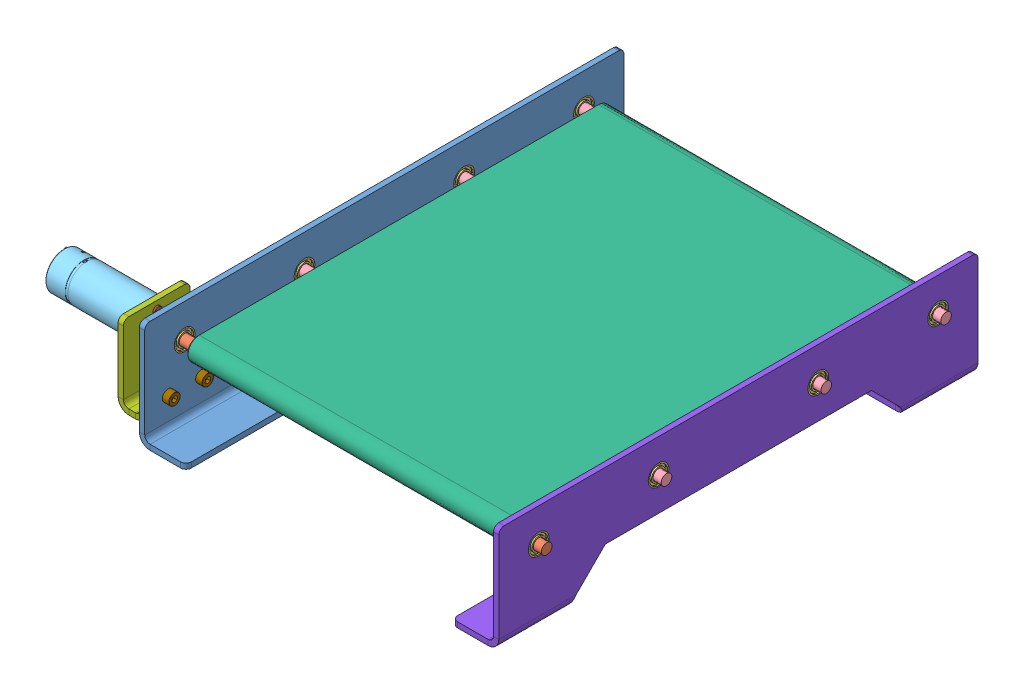
SolidWorks assembly Conveyor, configuration Default. Lengths in mm.
Overall size (367.55 80 360).
25 component instances, 11 part files, 54 mates.
Components (placement in the parent):
- ConveyorFrame2-1: ConveyorFrame2 [Default] at (-55.1725 55.3109 -170.5228) size (35 80 360)
- RollerMotorShaft-1: RollerMotorShaft [Default] at (200.8275 30.3109 159.4772) x (0 -0.190397 0.981707) z (-1 0 0) size (15 15 292)
- SKF - 618-8 - 12,SI,NC,12_68-4: SKF - 618-8 - 12,SI,NC,12_68 [SKF - 618-8 - 12,SI,NC,12_68] at (-53.1725 30.3109 -140.5228) x (-1 0 0) z (0 -0.925656 -0.378366) size (4 16 16)
- SKF - 618-8 - 12,SI,NC,12_68-5: SKF - 618-8 - 12,SI,NC,12_68 [SKF - 618-8 - 12,SI,NC,12_68] at (-53.1725 30.3109 -50.5228) size (4 16 16)
- SKF - 618-8 - 12,SI,NC,12_68-6: SKF - 618-8 - 12,SI,NC,12_68 [SKF - 618-8 - 12,SI,NC,12_68] at (-53.1725 30.3109 69.4772) x (1 0 0) z (0 0.002709 0.999996) size (4 16 16)
- SKF - 618-8 - 12,SI,NC,12_68-7: SKF - 618-8 - 12,SI,NC,12_68 [SKF - 618-8 - 12,SI,NC,12_68] at (-53.1725 30.3109 159.4772) size (4 16 16)
- SKF - 618-8 - 12,SI,NC,12_68-8: SKF - 618-8 - 12,SI,NC,12_68 [SKF - 618-8 - 12,SI,NC,12_68] at (212.8275 30.3109 -140.5228) x (1 0 0) z (0 -0.084259 0.996444) size (4 16 16)
- SKF - 618-8 - 12,SI,NC,12_68-9: SKF - 618-8 - 12,SI,NC,12_68 [SKF - 618-8 - 12,SI,NC,12_68] at (212.8275 30.3109 -50.5228) size (4 16 16)
- SKF - 618-8 - 12,SI,NC,12_68-10: SKF - 618-8 - 12,SI,NC,12_68 [SKF - 618-8 - 12,SI,NC,12_68] at (212.8275 30.3109 69.4772) x (1 0 0) z (0 0.283229 0.959052) size (4 16 16)
- SKF - 618-8 - 12,SI,NC,12_68-11: SKF - 618-8 - 12,SI,NC,12_68 [SKF - 618-8 - 12,SI,NC,12_68] at (212.8275 30.3109 159.4772) x (1 0 0) z (0 0.083715 0.99649) size (4 16 16)
- Roller-2: Roller [Default] at (-41.1725 30.3109 69.4772) x (0 0 -1) z (1 0 0) size (15 15 282)
- Roller-3: Roller [Default] at (-41.1725 30.3109 -140.5228) x (0 0 -1) z (1 0 0) size (15 15 282)
- Roller-4: Roller [Default] at (200.8275 30.3109 -50.5228) x (0 0.924225 0.381849) z (-1 0 0) size (15 15 282)
- DC_MOTOR_(Brushless DC Inrunner Motor)-1: DC_MOTOR_(Brushless DC Inrunner Motor) [Default] at (-76.1725 30.3109 159.4772) x (1 0 0) z (0 0.866025 0.5) size (82.15 28 28)
- ConveyorBelt-1: ConveyorBelt [Default] at (-40.1725 12.0227 98.7904) x (0 0 -1) z (1 0 0) size (317 17 240)
- MotorBracketConveyor-1: MotorBracketConveyor [Default] at (-76.1725 45.3109 184.4772) x (0 0 -1) z (1 0 0) size (50 60 21)
- ConveyorFrame-4: ConveyorFrame [Default] at (214.8275 55.3109 189.4772) x (-1 0 0) z (0 0 -1) size (35 80 360)
- IS 2269 - M5 x 16-N-1: IS 2269 - M5 x 16-N [IS 2269 - M5 x 16-N] at (-46.1725 0.3109 146.9772) x (-1 0 0) z (0 0.924225 0.381849) size (21 8.5 8.5)
- IS 2269 - M5 x 16-N-2: IS 2269 - M5 x 16-N [IS 2269 - M5 x 16-N] at (-46.1725 0.3109 171.9772) x (-1 0 0) z (0 0.924225 0.381849) size (21 8.5 8.5)
- IS 1363-2 - M5-N-1: IS 1363-2 - M5-N [IS 1363-2 - M5-N] at (-64.7725 0.3109 146.9772) x (0 0 1) z (-1 0 0) size (8 9.24 5.6)
- IS 1363-2 - M5-N-2: IS 1363-2 - M5-N [IS 1363-2 - M5-N] at (-64.7725 0.3109 171.9772) x (0 0 1) z (-1 0 0) size (8 9.24 5.6)
- IS 7483 - M3 x 6 - Z -- 6N-1: IS 7483 - M3 x 6 - Z -- 6N [IS 7483 - M3 x 6 - Z -- 6N] at (-69.7725 30.3109 168.4772) x (-1 0 0) z (0 -0.924225 -0.381849) size (8.35 5.6 5.6)
- IS 7483 - M3 x 6 - Z -- 6N-2: IS 7483 - M3 x 6 - Z -- 6N [IS 7483 - M3 x 6 - Z -- 6N] at (-69.7725 21.3109 159.4772) x (-1 0 0) z (0 0 1) size (8.35 5.6 5.6)
- IS 7483 - M3 x 6 - Z -- 6N-3: IS 7483 - M3 x 6 - Z -- 6N [IS 7483 - M3 x 6 - Z -- 6N] at (-69.7725 39.3109 159.4772) x (-1 0 0) z (0 -0.924225 -0.381849) size (8.35 5.6 5.6)
- IS 7483 - M3 x 6 - Z -- 6N-4: IS 7483 - M3 x 6 - Z -- 6N [IS 7483 - M3 x 6 - Z -- 6N] at (-69.7725 30.3109 150.4772) x (-1 0 0) z (0 -0.924225 -0.381849) size (8.35 5.6 5.6)
Mates (geometry in assembly coordinates):
- Concentric15: concentric anti-aligned: cylinder of RollerMotorShaft-1 through (220.8275 30.3109 159.4772) axis (-1 0 0) radius 4; cylinder of SKF - 618-8 - 12,SI,NC,12_68-11 through (192.19 30.3109 159.4772) axis (1 0 0) radius 4
- Concentric16: concentric anti-aligned: cylinder of SKF - 618-8 - 12,SI,NC,12_68-10 through (192.19 30.3109 69.4772) axis (1 0 0) radius 4; cylinder of Roller-2 through (220.8275 30.3109 69.4772) axis (-1 0 0) radius 4
- Concentric17: concentric aligned: cylinder of SKF - 618-8 - 12,SI,NC,12_68-5 through (-73.81 30.3109 -50.5228) axis (1 0 0) radius 4; cylinder of Roller-4 through (-61.1725 30.3109 -50.5228) axis (1 0 0) radius 4
- Concentric18: concentric anti-aligned: cylinder of SKF - 618-8 - 12,SI,NC,12_68-8 through (192.19 30.3109 -140.5228) axis (1 0 0) radius 4; cylinder of Roller-3 through (220.8275 30.3109 -140.5228) axis (-1 0 0) radius 4
- Concentric22: concentric aligned: cylinder of Roller-3 through (200.8275 30.3109 -140.5228) axis (-1 0 0) radius 7.5; cylinder of ConveyorBelt-1 through (199.8275 30.3109 -140.5228) axis (-1 0 0) radius 7.5
- Concentric23: concentric anti-aligned: cylinder of RollerMotorShaft-1 through (-71.1725 30.3109 159.4772) axis (1 0 0) radius 4; cylinder of DC_MOTOR_(Brushless DC Inrunner Motor)-1 through (-64.5725 30.3109 159.4772) axis (-1 0 0) radius 1.5875
- Distance8: distance = 2 mm anti-aligned: plane of RollerMotorShaft-1 through (-71.1725 30.3109 159.4772) normal (-1 0 0); plane of DC_MOTOR_(Brushless DC Inrunner Motor)-1 through (-73.1725 30.3109 159.4772) normal (1 0 0)
- Concentric26: concentric aligned: cylinder of RollerMotorShaft-1 through (-71.1725 30.3109 159.4772) axis (1 0 0) radius 4; cylinder of MotorBracketConveyor-1 through (-72.1725 30.3109 159.4772) axis (1 0 0) radius 5.5
- Coincident20: coincident anti-aligned: plane of DC_MOTOR_(Brushless DC Inrunner Motor)-1 through (-76.1725 30.3109 159.4772) normal (1 0 0); plane of MotorBracketConveyor-1 through (-76.1725 -10.6891 134.4772) normal (-1 0 0)
- Concentric27: concentric aligned: cylinder of DC_MOTOR_(Brushless DC Inrunner Motor)-1 through (-83.1725 39.3109 159.4772) axis (1 0 0) radius 1.5; cylinder of MotorBracketConveyor-1 through (-72.1725 39.3109 159.4772) axis (1 0 0) radius 1.5
- Distance10: distance = 270 mm anti-aligned: plane of ConveyorFrame2-1 through (-55.1725 -20.6891 189.4772) normal (-1 0 0); plane of ConveyorFrame-4 through (214.8275 -20.6891 -170.5228) normal (1 0 0)
- Distance11: distance = 10 mm anti-aligned: plane of Roller-2 through (-41.1725 30.3109 69.4772) normal (-1 0 0); plane of ConveyorFrame2-1 through (-51.1725 -20.6891 189.4772) normal (1 0 0)
- Distance12: distance = 10 mm anti-aligned: plane of Roller-4 through (-41.1725 30.3109 -50.5228) normal (-1 0 0); plane of ConveyorFrame2-1 through (-51.1725 -20.6891 189.4772) normal (1 0 0)
- Distance13: distance = 10 mm anti-aligned: plane of ConveyorFrame2-1 through (-51.1725 -20.6891 189.4772) normal (1 0 0); plane of Roller-3 through (-41.1725 30.3109 -140.5228) normal (-1 0 0)
- Concentric29: concentric anti-aligned: cylinder of SKF - 618-8 - 12,SI,NC,12_68-4 through (-32.535 30.3109 -140.5228) axis (-1 0 0) radius 4; cylinder of Roller-3 through (-61.1725 30.3109 -140.5228) axis (1 0 0) radius 4
- Concentric30: concentric aligned: cylinder of SKF - 618-8 - 12,SI,NC,12_68-5 through (-73.81 30.3109 -50.5228) axis (1 0 0) radius 4; cylinder of Roller-4 through (-61.1725 30.3109 -50.5228) axis (1 0 0) radius 4
- Concentric31: concentric aligned: cylinder of SKF - 618-8 - 12,SI,NC,12_68-6 through (-73.81 30.3109 69.4772) axis (1 0 0) radius 4; cylinder of Roller-2 through (-61.1725 30.3109 69.4772) axis (1 0 0) radius 4
- Concentric32: concentric aligned: cylinder of RollerMotorShaft-1 through (-71.1725 30.3109 159.4772) axis (1 0 0) radius 4; cylinder of SKF - 618-8 - 12,SI,NC,12_68-7 through (-73.81 30.3109 159.4772) axis (1 0 0) radius 4
- Concentric33: concentric aligned: cylinder of ConveyorFrame2-1 through (-51.1725 0.3109 171.9772) axis (-1 0 0) radius 2.5; cylinder of MotorBracketConveyor-1 through (-59.1725 0.3109 171.9772) axis (-1 0 0) radius 2.5
- Coincident28: coincident anti-aligned: plane of ConveyorFrame2-1 through (-55.1725 -20.6891 189.4772) normal (-1 0 0); plane of MotorBracketConveyor-1 through (-55.1725 15.3109 134.4772) normal (1 0 0)
- Coincident29: coincident anti-aligned: plane of DC_MOTOR_(Brushless DC Inrunner Motor)-1 through (-76.1725 30.3109 159.4772) normal (1 0 0); plane of MotorBracketConveyor-1 through (-76.1725 -10.6891 134.4772) normal (-1 0 0)
- Concentric36: concentric anti-aligned: cylinder of ConveyorFrame2-1 through (-51.1725 30.3109 159.4772) axis (-1 0 0) radius 7.75; cylinder of SKF - 618-8 - 12,SI,NC,12_68-7 through (-73.81 30.3109 159.4772) axis (1 0 0) radius 8
- Concentric37: concentric anti-aligned: cylinder of ConveyorFrame2-1 through (-51.1725 30.3109 69.4772) axis (-1 0 0) radius 7.75; cylinder of SKF - 618-8 - 12,SI,NC,12_68-6 through (-73.81 30.3109 69.4772) axis (1 0 0) radius 8
- Coincident30: coincident aligned: plane of ConveyorFrame2-1 through (-55.1725 -20.6891 189.4772) normal (-1 0 0); plane of SKF - 618-8 - 12,SI,NC,12_68-6 through (-55.1725 37.1109 69.4588) normal (-1 0 0)
- Concentric38: concentric anti-aligned: cylinder of ConveyorFrame2-1 through (-51.1725 30.3109 -50.5228) axis (-1 0 0) radius 7.75; cylinder of SKF - 618-8 - 12,SI,NC,12_68-5 through (-73.81 30.3109 -50.5228) axis (1 0 0) radius 8
- Coincident31: coincident aligned: plane of ConveyorFrame2-1 through (-55.1725 -20.6891 189.4772) normal (-1 0 0); plane of SKF - 618-8 - 12,SI,NC,12_68-5 through (-55.1725 35.5109 -50.5228) normal (-1 0 0)
- Coincident32: coincident aligned: plane of ConveyorFrame2-1 through (-55.1725 -20.6891 189.4772) normal (-1 0 0); plane of SKF - 618-8 - 12,SI,NC,12_68-4 through (-55.1725 33.2622 -147.7429) normal (-1 0 0)
- Concentric39: concentric aligned: cylinder of ConveyorFrame2-1 through (-51.1725 30.3109 -140.5228) axis (-1 0 0) radius 7.75; cylinder of SKF - 618-8 - 12,SI,NC,12_68-4 through (-32.535 30.3109 -140.5228) axis (-1 0 0) radius 8
- Concentric40: concentric aligned: cylinder of SKF - 618-8 - 12,SI,NC,12_68-8 through (192.19 30.3109 -140.5228) axis (1 0 0) radius 8; cylinder of ConveyorFrame-4 through (210.8275 30.3109 -140.5228) axis (1 0 0) radius 7.75
- Coincident33: coincident aligned: plane of SKF - 618-8 - 12,SI,NC,12_68-8 through (214.8275 38.0832 -139.8655) normal (1 0 0); plane of ConveyorFrame-4 through (214.8275 -20.6891 -170.5228) normal (1 0 0)
- Coincident34: coincident aligned: plane of SKF - 618-8 - 12,SI,NC,12_68-9 through (214.8275 38.1109 -50.5228) normal (1 0 0); plane of ConveyorFrame-4 through (214.8275 -20.6891 -170.5228) normal (1 0 0)
- Concentric41: concentric aligned: cylinder of SKF - 618-8 - 12,SI,NC,12_68-9 through (192.19 30.3109 -50.5228) axis (1 0 0) radius 8; cylinder of ConveyorFrame-4 through (210.8275 30.3109 -50.5228) axis (1 0 0) radius 7.75
- Concentric42: concentric aligned: cylinder of SKF - 618-8 - 12,SI,NC,12_68-10 through (192.19 30.3109 69.4772) axis (1 0 0) radius 8; cylinder of ConveyorFrame-4 through (210.8275 30.3109 69.4772) axis (1 0 0) radius 7.75
- Coincident35: coincident aligned: plane of SKF - 618-8 - 12,SI,NC,12_68-10 through (214.8275 37.7915 67.2681) normal (1 0 0); plane of ConveyorFrame-4 through (214.8275 -20.6891 -170.5228) normal (1 0 0)
- Concentric43: concentric aligned: cylinder of SKF - 618-8 - 12,SI,NC,12_68-11 through (192.19 30.3109 159.4772) axis (1 0 0) radius 8; cylinder of ConveyorFrame-4 through (210.8275 30.3109 159.4772) axis (1 0 0) radius 7.75
- Coincident36: coincident aligned: plane of SKF - 618-8 - 12,SI,NC,12_68-11 through (214.8275 38.0835 158.8243) normal (1 0 0); plane of ConveyorFrame-4 through (214.8275 -20.6891 -170.5228) normal (1 0 0)
- Distance14: distance = 1 mm aligned: plane of ConveyorBelt-1 through (-40.1725 30.3109 159.4772) normal (-1 0 0); plane of Roller-3 through (-41.1725 30.3109 -140.5228) normal (-1 0 0)
- Parallel6: parallel aligned: plane of ConveyorFrame2-1 through (-51.1725 55.3109 189.4772) normal (0 1 0); plane of ConveyorBelt-1 through (199.8275 38.8109 159.4772) normal (0 1 0)
- Concentric44: concentric anti-aligned: cylinder of MotorBracketConveyor-1 through (-59.1725 0.3109 146.9772) axis (-1 0 0) radius 2.5; cylinder of IS 2269 - M5 x 16-N-1 through (-46.1725 0.3109 146.9772) axis (1 0 0) radius 2.5
- Concentric45: concentric anti-aligned: cylinder of MotorBracketConveyor-1 through (-59.1725 0.3109 171.9772) axis (-1 0 0) radius 2.5; cylinder of IS 2269 - M5 x 16-N-2 through (-46.1725 0.3109 171.9772) axis (1 0 0) radius 2.5
- Coincident40: coincident anti-aligned: plane of ConveyorFrame2-1 through (-51.1725 -20.6891 189.4772) normal (1 0 0); plane of IS 2269 - M5 x 16-N-1 through (-51.1725 -1.3119 150.9052) normal (-1 0 0)
- Coincident41: coincident anti-aligned: plane of ConveyorFrame2-1 through (-51.1725 -20.6891 189.4772) normal (1 0 0); plane of IS 2269 - M5 x 16-N-2 through (-51.1725 -1.3119 175.9052) normal (-1 0 0)
- Concentric46: concentric anti-aligned: cylinder of IS 2269 - M5 x 16-N-2 through (-46.1725 0.3109 171.9772) axis (1 0 0) radius 2.5; cylinder of IS 1363-2 - M5-N-2 through (-59.1725 0.3109 171.9772) axis (-1 0 0) radius 2.1
- Concentric47: concentric anti-aligned: cylinder of IS 2269 - M5 x 16-N-1 through (-46.1725 0.3109 146.9772) axis (1 0 0) radius 2.5; cylinder of IS 1363-2 - M5-N-1 through (-59.1725 0.3109 146.9772) axis (-1 0 0) radius 2.1
- Coincident42: coincident anti-aligned: plane of MotorBracketConveyor-1 through (-59.1725 15.3109 134.4772) normal (-1 0 0); plane of IS 1363-2 - M5-N-2 through (-59.1725 4.9297 171.9772) normal (1 0 0)
- Coincident43: coincident anti-aligned: plane of MotorBracketConveyor-1 through (-59.1725 15.3109 134.4772) normal (-1 0 0); plane of IS 1363-2 - M5-N-1 through (-59.1725 4.9297 146.9772) normal (1 0 0)
- Coincident44: coincident anti-aligned: plane of MotorBracketConveyor-1 through (-72.1725 -10.6891 134.4772) normal (1 0 0); plane of IS 7483 - M3 x 6 - Z -- 6N-4 through (-72.1725 30.8837 149.0909) normal (-1 0 0)
- Coincident45: coincident anti-aligned: plane of MotorBracketConveyor-1 through (-72.1725 -10.6891 134.4772) normal (1 0 0); plane of IS 7483 - M3 x 6 - Z -- 6N-3 through (-72.1725 39.8837 158.0909) normal (-1 0 0)
- Coincident46: coincident anti-aligned: plane of MotorBracketConveyor-1 through (-72.1725 -10.6891 134.4772) normal (1 0 0); plane of IS 7483 - M3 x 6 - Z -- 6N-1 through (-72.1725 30.8837 167.0909) normal (-1 0 0)
- Coincident47: coincident anti-aligned: plane of MotorBracketConveyor-1 through (-72.1725 -10.6891 134.4772) normal (1 0 0); plane of IS 7483 - M3 x 6 - Z -- 6N-2 through (-72.1725 19.8109 159.4772) normal (-1 0 0)
- Concentric48: concentric aligned: cylinder of MotorBracketConveyor-1 through (-72.1725 21.3109 159.4772) axis (1 0 0) radius 1.5; cylinder of IS 7483 - M3 x 6 - Z -- 6N-2 through (-69.7725 21.3109 159.4772) axis (1 0 0) radius 1.5
- Concentric49: concentric aligned: cylinder of MotorBracketConveyor-1 through (-72.1725 30.3109 168.4772) axis (1 0 0) radius 1.5; cylinder of IS 7483 - M3 x 6 - Z -- 6N-1 through (-69.7725 30.3109 168.4772) axis (1 0 0) radius 1.5
- Concentric50: concentric aligned: cylinder of MotorBracketConveyor-1 through (-72.1725 39.3109 159.4772) axis (1 0 0) radius 1.5; cylinder of IS 7483 - M3 x 6 - Z -- 6N-3 through (-69.7725 39.3109 159.4772) axis (1 0 0) radius 1.5
- Concentric51: concentric aligned: cylinder of MotorBracketConveyor-1 through (-72.1725 30.3109 150.4772) axis (1 0 0) radius 1.5; cylinder of IS 7483 - M3 x 6 - Z -- 6N-4 through (-69.7725 30.3109 150.4772) axis (1 0 0) radius 1.5
